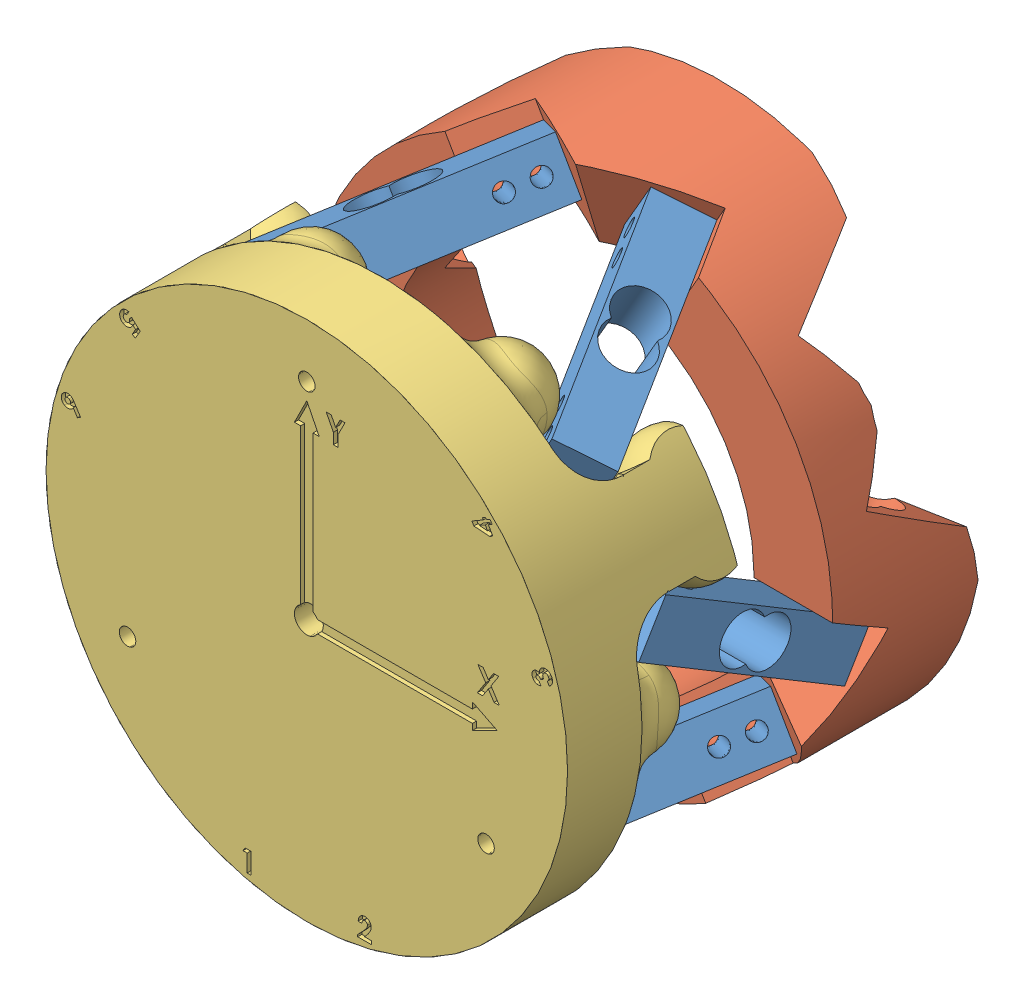
SolidWorks assembly Capteur 6 axes V2, configuration Défaut. Lengths in mm.
Overall size (126 126 100).
8 component instances, 3 part files, 19 mates.
Components (placement in the parent):
- Cellule_2kg-1: Cellule_2kg [Défaut] at (51.9615 0 50) x (1 0 0) z (0 -0.514496 -0.857493) size (12.7 12.7 58)
- Cellule_2kg-2: Cellule_2kg [Défaut] at (25.9808 45 50) x (0.5 0.866025 0) z (0.445566 -0.257248 0.857493) size (12.7 12.7 58)
- Cellule_2kg-3: Cellule_2kg [Défaut] at (-25.9808 45 50) x (0.5 -0.866025 0) z (-0.445566 -0.257248 0.857493) size (12.7 12.7 58)
- Cellule_2kg-4: Cellule_2kg [Défaut] at (-51.9615 0 50) x (1 0 0) z (0 -0.514496 -0.857493) size (12.7 12.7 58)
- Cellule_2kg-5: Cellule_2kg [Défaut] at (-25.9808 -45 50) x (0.5 0.866025 0) z (0.445566 -0.257248 0.857493) size (12.7 12.7 58)
- Cellule_2kg-6: Cellule_2kg [Défaut] at (25.9808 -45 50) x (0.5 -0.866025 0) z (-0.445566 -0.257248 0.857493) size (12.7 12.7 58)
- Bâti^Capteur 6 axes V2-1: Bâti^Capteur 6 axes V2 [Défaut] at origin size (126 126 36) (virtual)
- Socle^Capteur 6 axes V2-1: Socle^Capteur 6 axes V2 [Défaut] at origin size (126 126 44.09) (virtual)
Mates (geometry in assembly coordinates):
- Coïncidente1: coincident anti-aligned: line of Cellule_2kg-1 through (51.9615 16.6954 77.8256) axis (0 -0.514496 -0.857493); line of assembly
- Coïncidente2: coincident: point of Cellule_2kg-1; plane of assembly
- Coïncidente3: coincident anti-aligned: line of Cellule_2kg-2 through (11.5221 53.3477 22.1744) axis (0.445566 -0.257248 0.857493); line of assembly
- Coïncidente4: coincident: point of Cellule_2kg-2; plane of assembly
- Coïncidente5: coincident aligned: line of Cellule_2kg-3 through (-11.5221 53.3477 22.1744) axis (-0.445566 -0.257248 0.857493); line of assembly
- Coïncidente6: coincident: point of Cellule_2kg-3; plane of assembly
- Coïncidente7: coincident aligned: line of Cellule_2kg-4 through (-51.9615 16.6954 77.8256) axis (0 -0.514496 -0.857493); line of assembly
- Coïncidente8: coincident: point of Cellule_2kg-4; plane of assembly
- Coïncidente9: coincident aligned: line of Cellule_2kg-5 through (-40.4394 -36.6523 22.1744) axis (0.445566 -0.257248 0.857493); line of assembly
- Coïncidente10: coincident: point of Cellule_2kg-5; plane of assembly
- Coïncidente11: coincident anti-aligned: line of Cellule_2kg-6 through (40.4394 -36.6523 22.1744) axis (-0.445566 -0.257248 0.857493); line of assembly
- Coïncidente12: coincident: point of Cellule_2kg-6; plane of assembly
- Coïncidente15: coincident: line of Cellule_2kg-1 through (62.6865 0 50) axis (-1 0 0); point of assembly
- Coïncidente16: coincident: line of Cellule_2kg-2 through (31.3433 54.2881 50) axis (-0.5 -0.866025 0); point of assembly
- Coïncidente17: coincident: line of Cellule_2kg-3 through (-20.6183 35.7119 50) axis (-0.5 0.866025 0); point of assembly
- Coïncidente18: coincident: line of Cellule_2kg-4 through (-41.2365 0 50) axis (-1 0 0); point of assembly
- Coïncidente19: coincident: line of Cellule_2kg-5 through (-20.6183 -35.7119 50) axis (-0.5 -0.866025 0); point of assembly
- Coïncidente20: coincident: line of Cellule_2kg-6 through (31.3433 -54.2881 50) axis (-0.5 0.866025 0); point of assembly
- Coïncidente21: coordinate: point of Bâti^Capteur 6 axes V2-1; point of Socle^Capteur 6 axes V2-1
